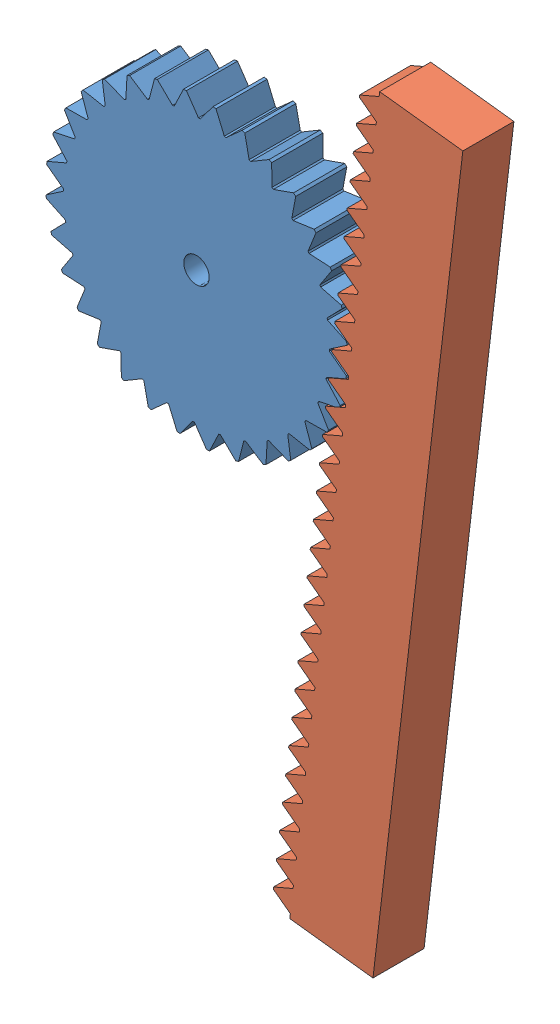
SolidWorks assembly rackandpinion, configuration Default. Lengths in mm.
Overall size (91.77 151.31 10).
2 component instances, 2 part files, 3 mates.
Components (placement in the parent):
- gear_pinion-1: gear_pinion [Default] at (24.7537 27.5615 41.8226) x (0.452272 -0.89188 0) z (0 0 1) size (59 59 10)
- rack-1: rack [Default] at (39.4328 -72.8056 41.8226) x (0.117208 0.993107 0) z (0 0 1) size (150 20 10)
Mates (geometry in assembly coordinates):
- Coincident1: coincident aligned: plane of gear_pinion-1 through (24.7537 27.5615 51.8226) normal (0 0 1); plane of rack-1 through (39.4328 -72.8056 51.8226) normal (0 0 1)
- Distance3: distance = 47.4084 mm: line of assembly; point of gear_pinion-1; line of rack-1 through (59.2949 -75.1498 41.8226) axis (0.117208 0.993107 0)
- RackPinionMate3: rack pinion = 52 mm: line of rack-1 through (59.2949 -75.1498 41.8226) axis (0.117208 0.993107 0); circle of gear_pinion-1
